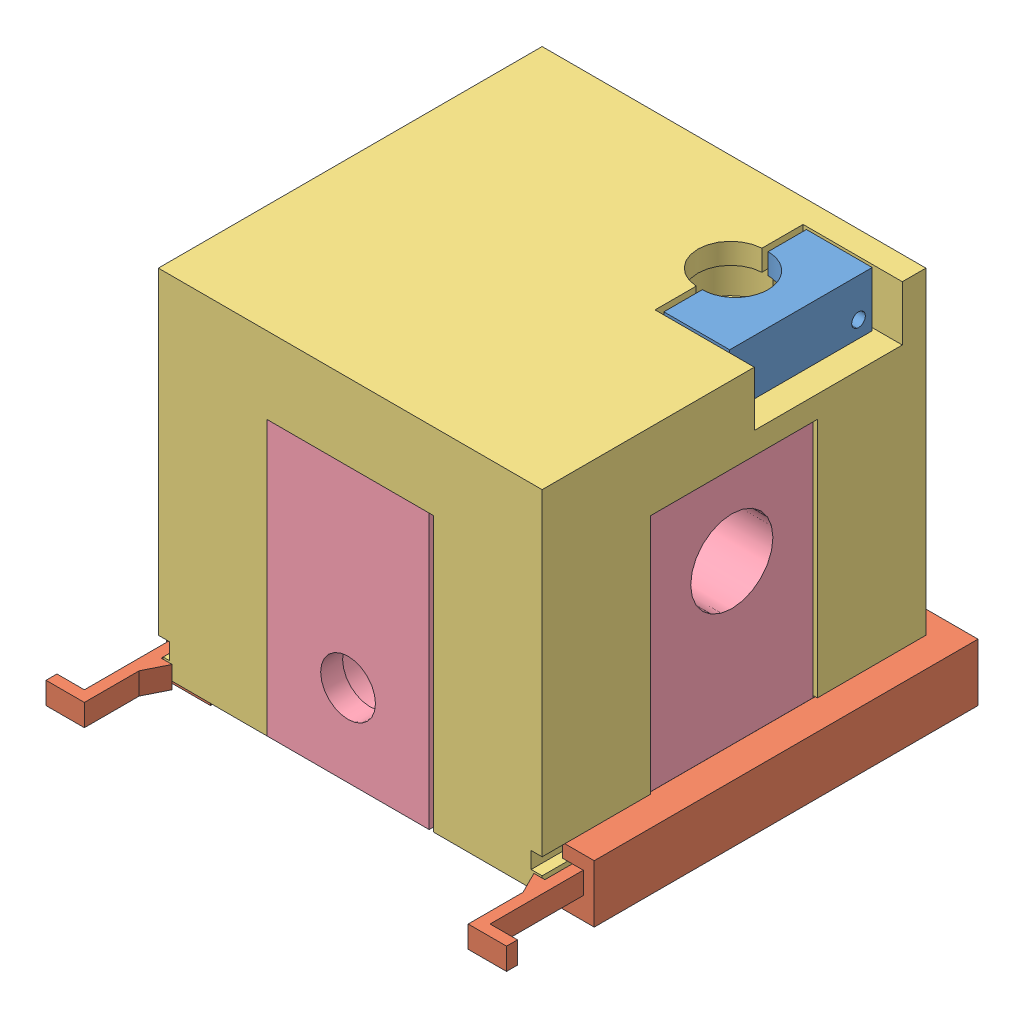
SolidWorks assembly P3DMIPC-Tête_complete, configuration Défaut. Lengths in mm.
Overall size (84 69 89).
4 component instances, 4 part files, 3 mates.
Components (placement in the parent):
- P3DMIPC-Clip_Buse_E3D-1: P3DMIPC-Clip_Buse_E3D [Défaut] at (17.0518 23.4109 40.0035) x (1 0 0) z (0 1 0) size (12 26 10)
- P3DMIPC-Clip_tête-1: P3DMIPC-Clip_tête [Défaut] at (26.9018 -25.0891 4.5597) x (1 0 0) z (0 -1 0) size (84 89 10.5)
- P3DMIPC-Porte_Buse_E3DX1-1: P3DMIPC-Porte_Buse_E3DX1 [Défaut] at (22.03 33.4019 79.1927) x (0 0 1) z (0 -1 0) size (70 70 64)
- P3DMIPC-Chariot-1: P3DMIPC-Chariot [Défaut] at (-48.37 -30.5981 79.1927) size (70 50 70)
Mates (geometry in assembly coordinates):
- Coïncidente19: coincident: plane of P3DMIPC-Porte_Buse_E3DX1-1 through (22.03 19.4019 79.1927) normal (0 -1 0); plane of P3DMIPC-Chariot-1 through (21.63 19.4019 79.1927) normal (0 1 0)
- Coïncidente20: coincident: plane of P3DMIPC-Porte_Buse_E3DX1-1 through (-28.17 19.4019 79.1927) normal (1 0 0); plane of P3DMIPC-Chariot-1 through (-28.17 19.4019 79.1927) normal (-1 0 0)
- Coïncidente21: coincident aligned: plane of P3DMIPC-Porte_Buse_E3DX1-1 through (22.03 -30.5981 79.1927) normal (0 0 1); plane of P3DMIPC-Chariot-1 through (21.63 -30.5981 79.1927) normal (0 0 1)
